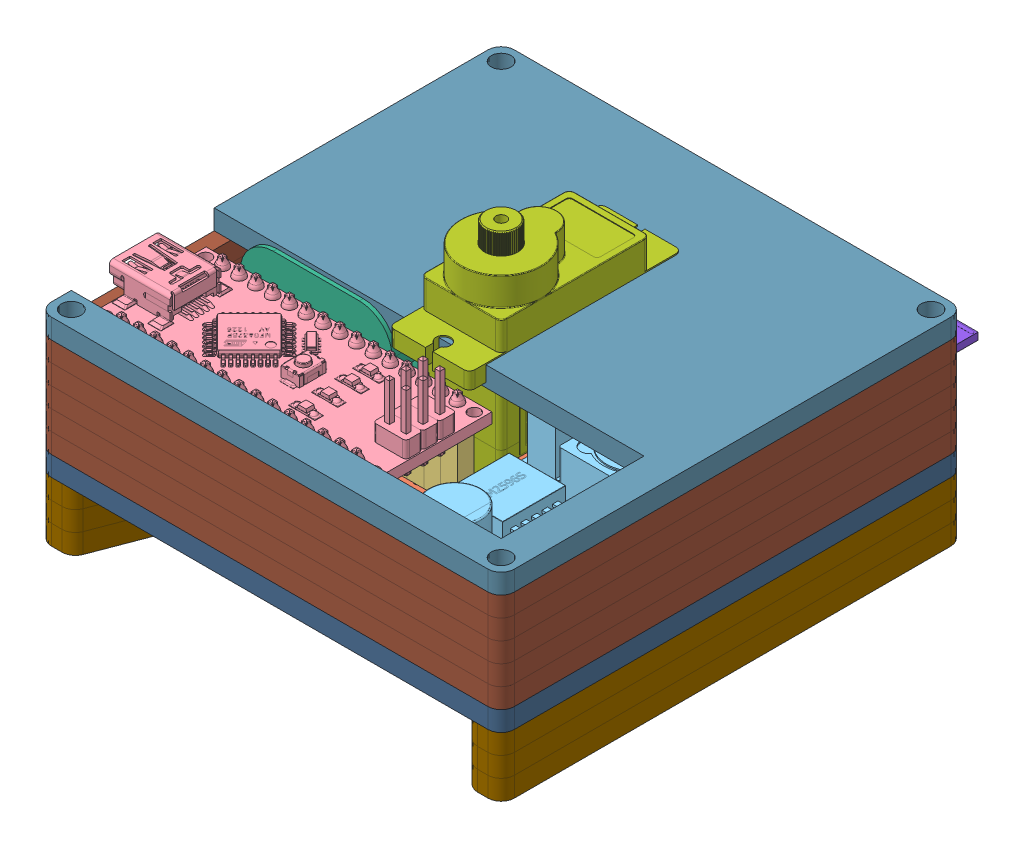
SolidWorks assembly base assembly, configuration Default. Lengths in mm.
Overall size (70 41.85 79.11).
27 component instances, 14 part files, 68 mates.
Components (placement in the parent):
- hex nut style 1_am-1: hex nut style 1_am [B18.2.4.1M - Hex nut, Style 1,  M3 x 0.5 --D-N] at (-15.0478 14.4 2.5048) x (1 0 0) z (0 1 0) size (5.5 6.35 2.4)
- hex nut style 1_am-2: hex nut style 1_am [B18.2.4.1M - Hex nut, Style 1,  M3 x 0.5 --D-N] at (-65.0478 12 2.5048) x (1 0 0) z (0 -1 0) size (5.5 6.35 2.4)
- hex nut style 1_am-3: hex nut style 1_am [B18.2.4.1M - Hex nut, Style 1,  M3 x 0.5 --D-N] at (-15.0478 14.4 52.5048) x (1 0 0) z (0 1 0) size (5.5 6.35 2.4)
- hex nut style 1_am-4: hex nut style 1_am [B18.2.4.1M - Hex nut, Style 1,  M3 x 0.5 --D-N] at (-65.0478 14.4 52.5048) x (1 0 0) z (0 1 0) size (5.5 6.35 2.4)
- pcb-2: pcb [Default] at (-72.9594 14.4 41.2771) x (0 0 1) z (-1 0 0) size (60 1 60)
- Arduino NanoV3 + Female Headers-1: Arduino NanoV3 + Female Headers [Default] at (-32.0594 27.95 40.8489) x (-1 0 0) z (0 0 1) size (38.1 11.45 17.78)
- arduino nano-1: arduino nano [Default] at (-36.1294 26.35 42.1189) x (-1 0 0) z (0 0 -1) size (45 18.6 18)
- LM2596 - small buck-1: LM2596 - small buck [Default] at (-14.6157 36.0469 15.8857) x (0 0 1) z (0 1 0) size (43.33 21.52 14.13)
- battery-1: battery [Default] at (-61.9173 22.4 17.6773) size (23 7 40)
- battery-2: battery [Default] at (-61.709 15.4 17.6773) size (23 7 40)
- SG90 - Micro Servo 9g - Tower Pro.1-1: SG90 - Micro Servo 9g - Tower Pro.1 [Peça] at (-42.9594 22.55 23.5273) x (0 0 -1) z (1 0 0) size (32.1 29.95 12.4)
- nRF24L01+_enhanced-1: nRF24L01+_enhanced [Default<As Machined>] at (-22.4594 18.449 -0.9285) x (0 0 -1) z (1 0 0) size (29 12.85 15)
- stage-1: stage [Default] at (-42.9594 0 28.6773) size (70 3 70)
- base1-1: base1 [Default] at (-42.9594 12 28.6773) x (-1 0 0) z (0 0 1) size (70 3 70)
- stage-2: stage [Default] at (-42.9594 3 28.6773) size (70 3 70)
- stage-3: stage [Default] at (-42.9594 6 28.6773) size (70 3 70)
- walls-1: walls [Default] at (-42.9594 12 28.6773) size (70 3 70)
- walls-2: walls [Default] at (-42.9594 15 28.6773) size (70 3 70)
- walls-3: walls [Default] at (-42.9594 18 28.6773) size (70 3 70)
- walls-4: walls [Default] at (-42.9594 21 28.6773) size (70 3 70)
- walls-5: walls [Default] at (-42.9594 24 28.6773) size (70 3 70)
- Header, Male, 2.54mm, 1x3-1: Header, Male, 2.54mm, 1x3 [Default] at (-33.4499 15.146 0.698) x (0 0 -1) z (1 0 0) size (7.62 11.54 2.54)
- Header, Male, 2.54mm, 1x3-2: Header, Male, 2.54mm, 1x3 [Default] at (-36.3022 15.146 0.7513) x (0 0 -1) z (1 0 0) size (7.62 11.54 2.54)
- Header, Male, 2.54mm, 1x2-1: Header, Male, 2.54mm, 1x2 [Default] at (-44.122 15.146 5.6481) size (5.08 11.54 2.54)
- Header, Male, 2.54mm, 1x2-2: Header, Male, 2.54mm, 1x2 [Default] at (-44.0543 15.146 2.787) size (5.08 11.54 2.54)
- Header, Male, 2.54mm, 1x2-3: Header, Male, 2.54mm, 1x2 [Default] at (-43.947 15.146 -0.0213) size (5.08 11.54 2.54)
- base1nano-1: base1nano [Default] at (-42.9594 27 28.6773) x (0 0 1) z (-1 0 0) size (70 3 70)
Mates (geometry in assembly coordinates):
- Coincident28: coincident anti-aligned: plane of stage-1 through (-41.8131 0 2.8151) normal (0 -1 0); plane of assembly through (0 0 0) normal (0 1 0)
- Coincident29: coincident anti-aligned: plane of stage-1 through (-41.8131 3 2.8151) normal (0 1 0); plane of stage-2 through (-41.8131 3 2.8151) normal (0 -1 0)
- Coincident30: coincident aligned: plane of stage-1 through (-77.9594 3 -6.3227) normal (-1 0 0); plane of stage-2 through (-77.9594 6 -6.3227) normal (-1 0 0)
- Concentric11: concentric aligned: cylinder of stage-1 through (-75.4594 0 61.1773) axis (0 1 0) radius 1.4881; cylinder of stage-2 through (-75.4594 3 61.1773) axis (0 1 0) radius 1.4881
- Coincident31: coincident anti-aligned: plane of stage-2 through (-41.8131 6 2.8151) normal (0 1 0); plane of stage-3 through (-41.8131 6 2.8151) normal (0 -1 0)
- Coincident32: coincident aligned: plane of stage-1 through (-77.9594 3 -6.3227) normal (-1 0 0); plane of stage-3 through (-77.9594 9 -6.3227) normal (-1 0 0)
- Concentric12: concentric aligned: cylinder of stage-1 through (-75.4594 0 61.1773) axis (0 1 0) radius 1.4881; cylinder of stage-3 through (-75.4594 6 61.1773) axis (0 1 0) radius 1.4881
- Coincident35: coincident anti-aligned: plane of base1-1 through (-42.9594 9 28.6773) normal (0 -1 0); plane of stage-3 through (-41.8131 9 2.8151) normal (0 1 0)
- Coincident36: coincident aligned: plane of base1-1 through (-77.9594 9 -6.3227) normal (-1 0 0); plane of stage-2 through (-77.9594 6 -6.3227) normal (-1 0 0)
- Concentric14: concentric aligned: cylinder of base1-1 through (-75.4594 9 61.1773) axis (0 1 0) radius 1.5; cylinder of stage-3 through (-75.4594 6 61.1773) axis (0 1 0) radius 1.4881
- Coincident37: coincident anti-aligned: plane of base1-1 through (-42.9594 12 28.6773) normal (0 1 0); plane of walls-1 through (-42.9594 12 28.6773) normal (0 -1 0)
- Coincident38: coincident aligned: plane of base1-1 through (-77.9594 9 -6.3227) normal (-1 0 0); plane of walls-1 through (-77.9594 15 -6.3227) normal (-1 0 0)
- Concentric15: concentric anti-aligned: cylinder of base1-1 through (-75.4594 9 61.1773) axis (0 1 0) radius 1.5; cylinder of walls-1 through (-75.4594 15 61.1773) axis (0 -1 0) radius 1.5
- Coincident39: coincident anti-aligned: plane of walls-1 through (-42.9594 15 28.6773) normal (0 1 0); plane of walls-2 through (-42.9594 15 28.6773) normal (0 -1 0)
- Coincident40: coincident aligned: plane of base1-1 through (-77.9594 9 -6.3227) normal (-1 0 0); plane of walls-2 through (-77.9594 18 -6.3227) normal (-1 0 0)
- Concentric16: concentric anti-aligned: cylinder of base1-1 through (-75.4594 9 61.1773) axis (0 1 0) radius 1.5; cylinder of walls-2 through (-75.4594 18 61.1773) axis (0 -1 0) radius 1.5
- Coincident41: coincident aligned: plane of base1-1 through (-77.9594 9 -6.3227) normal (-1 0 0); plane of walls-3 through (-77.9594 21 -6.3227) normal (-1 0 0)
- Concentric17: concentric anti-aligned: cylinder of base1-1 through (-75.4594 9 61.1773) axis (0 1 0) radius 1.5; cylinder of walls-3 through (-75.4594 21 61.1773) axis (0 -1 0) radius 1.5
- Coincident42: coincident anti-aligned: plane of walls-2 through (-42.9594 18 28.6773) normal (0 1 0); plane of walls-3 through (-42.9594 18 28.6773) normal (0 -1 0)
- Coincident43: coincident aligned: plane of base1-1 through (-77.9594 9 -6.3227) normal (-1 0 0); plane of walls-4 through (-77.9594 24 -6.3227) normal (-1 0 0)
- Concentric18: concentric anti-aligned: cylinder of base1-1 through (-75.4594 9 61.1773) axis (0 1 0) radius 1.5; cylinder of walls-4 through (-75.4594 24 61.1773) axis (0 -1 0) radius 1.5
- Coincident44: coincident anti-aligned: plane of walls-3 through (-42.9594 21 28.6773) normal (0 1 0); plane of walls-4 through (-42.9594 21 28.6773) normal (0 -1 0)
- Coincident45: coincident aligned: plane of base1-1 through (-77.9594 9 -6.3227) normal (-1 0 0); plane of walls-5 through (-77.9594 27 -6.3227) normal (-1 0 0)
- Concentric19: concentric anti-aligned: cylinder of base1-1 through (-75.4594 9 61.1773) axis (0 1 0) radius 1.5; cylinder of walls-5 through (-75.4594 27 61.1773) axis (0 -1 0) radius 1.5
- Coincident46: coincident anti-aligned: plane of walls-4 through (-42.9594 24 28.6773) normal (0 1 0); plane of walls-5 through (-42.9594 24 28.6773) normal (0 -1 0)
- Coincident49: coincident anti-aligned: plane of hex nut style 1_am-3 through (-20.5478 12 52.5048) normal (0 -1 0); plane of base1-1 through (-42.9594 12 28.6773) normal (0 1 0)
- Concentric21: concentric aligned: cylinder of hex nut style 1_am-3 through (-15.0478 12 52.5048) axis (0 1 0) radius 1.25; circle of assembly
- Coincident50: coincident anti-aligned: plane of hex nut style 1_am-1 through (-20.5478 12 2.5048) normal (0 -1 0); plane of base1-1 through (-42.9594 12 28.6773) normal (0 1 0)
- Concentric22: concentric aligned: cylinder of hex nut style 1_am-1 through (-15.0478 12 2.5048) axis (0 1 0) radius 1.25; circle of assembly
- Coincident51: coincident anti-aligned: plane of hex nut style 1_am-4 through (-70.5478 12 52.5048) normal (0 -1 0); plane of base1-1 through (-42.9594 12 28.6773) normal (0 1 0)
- Concentric23: concentric aligned: cylinder of hex nut style 1_am-4 through (-65.0478 12 52.5048) axis (0 1 0) radius 1.25; circle of assembly
- Coincident52: coincident anti-aligned: plane of hex nut style 1_am-2 through (-70.5478 12 2.5048) normal (0 -1 0); plane of base1-1 through (-42.9594 12 28.6773) normal (0 1 0)
- Concentric24: concentric anti-aligned: cylinder of hex nut style 1_am-2 through (-65.0478 14.4 2.5048) axis (0 -1 0) radius 1.25; circle of assembly
- Coincident53: coincident anti-aligned: plane of hex nut style 1_am-4 through (-70.5478 14.4 52.5048) normal (0 1 0); plane of pcb-2 through (-72.9594 14.4 41.2771) normal (0 -1 0)
- Concentric25: concentric anti-aligned: cylinder of SG90 - Micro Servo 9g - Tower Pro.1-1 through (-42.9594 38.75 28.6773) axis (0 -1 0) radius 6.1; circle of assembly
- Parallel8: parallel aligned: plane of SG90 - Micro Servo 9g - Tower Pro.1-1 through (-48.2094 12 12.2773) normal (0 0 -1); plane of walls-5 through (-77.9594 27 -6.3227) normal (0 0 -1)
- Coincident55: coincident anti-aligned: plane of SG90 - Micro Servo 9g - Tower Pro.1-1 through (-37.7094 12 33.9273) normal (0 -1 0); circle of assembly
- Parallel10: parallel: plane of SG90 - Micro Servo 9g - Tower Pro.1-1 through (-49.0594 30.2 38.7273) normal (-1 0 0); line of assembly
- Coincident58: coincident anti-aligned: plane of pcb-2 through (-49.0594 15.4 39.8789) normal (1 0 0); plane of SG90 - Micro Servo 9g - Tower Pro.1-1 through (-49.0594 30.2 38.7273) normal (-1 0 0)
- Lock2: lock: unknown of pcb-2; unknown of walls-5
- Coincident60: coincident anti-aligned: plane of pcb-2 through (-72.9594 15.4 41.2771) normal (0 1 0); plane of battery-2 through (-61.709 15.4 17.6773) normal (0 -1 0)
- Coincident64: coincident aligned: plane of battery-1 through (-73.4173 29.4 37.6773) normal (0 0 1); plane of battery-2 through (-73.209 22.4 37.6773) normal (0 0 1)
- Coincident65: coincident anti-aligned: plane of battery-1 through (-61.9173 22.4 17.6773) normal (0 -1 0); plane of battery-2 through (-61.709 22.4 17.6773) normal (0 1 0)
- Distance2: distance = 26 mm aligned: plane of battery-2 through (-73.209 22.4 37.6773) normal (0 0 1); plane of walls-4 through (-77.9594 24 63.6773) normal (0 0 1)
- Coincident67: coincident anti-aligned: plane of pcb-2 through (-72.9594 15.4 41.2771) normal (0 1 0); plane of LM2596 - small buck-1 through (-23.7804 15.4 36.9128) normal (0 -1 0)
- Coincident68: coincident: line of pcb-2 through (-72.9594 15.4 58.6289) axis (1 0 0); plane of LM2596 - small buck-1 through (-16.909 16.9539 58.6289) normal (0 0 1)
- Coincident69: coincident anti-aligned: plane of pcb-2 through (-72.9594 15.4 41.2771) normal (0 1 0); plane of nRF24L01+_enhanced-1 through (-19.0894 15.4 10.8015) normal (0 -1 0)
- Distance3: distance = 2 mm: plane of nRF24L01+_enhanced-1 through (-14.9594 18.949 13.5715) normal (1 0 0); line of pcb-2 through (-12.9594 15.4 58.6289) axis (0 0 -1)
- Coincident72: coincident anti-aligned: plane of pcb-2 through (-72.9594 15.4 41.2771) normal (0 1 0); plane of Arduino NanoV3 + Female Headers-1 through (-58.9894 15.4 42.1189) normal (0 -1 0)
- Coincident73: coincident: line of pcb-2 through (-72.9594 15.4 58.6289) axis (1 0 0); plane of Arduino NanoV3 + Female Headers-1 through (-39.9394 15.4 58.6289) normal (0 0 1)
- Coincident74: coincident: line of pcb-2 through (-72.9594 15.4 -1.3711) axis (0 0 1); plane of Arduino NanoV3 + Female Headers-1 through (-72.9594 15.4 56.0889) normal (-1 0 0)
- Coincident75: coincident anti-aligned: plane of Arduino NanoV3 + Female Headers-1 through (-53.9094 23.85 57.3589) normal (0 1 0); plane of arduino nano-1 through (-36.8994 23.85 56.5889) normal (0 -1 0)
- Coincident76: coincident aligned: plane of Arduino NanoV3 + Female Headers-1 through (-50.0994 15.4 58.6289) normal (0 0 1); plane of arduino nano-1 through (-47.0594 23.85 58.6289) normal (0 0 1)
- Coincident77: coincident aligned: plane of Arduino NanoV3 + Female Headers-1 through (-34.8594 15.4 58.6289) normal (1 0 0); plane of arduino nano-1 through (-34.8594 23.85 58.1289) normal (1 0 0)
- Lock3: lock: unknown of base1-1
- Coincident79: coincident anti-aligned: plane of pcb-2 through (-72.9594 15.4 41.2771) normal (0 1 0); plane of Header, Male, 2.54mm, 1x3-1 through (-33.4499 15.4 5.778) normal (0 -1 0)
- Parallel13: parallel: line of pcb-2 through (-12.9594 15.4 58.6289) axis (0 0 -1); plane of Header, Male, 2.54mm, 1x3-1 through (-34.7199 17.686 4.508) normal (-1 0 0)
- Coincident81: coincident anti-aligned: plane of pcb-2 through (-72.9594 15.4 41.2771) normal (0 1 0); plane of Header, Male, 2.54mm, 1x3-2 through (-36.3022 15.4 5.8313) normal (0 -1 0)
- Parallel14: parallel: line of pcb-2 through (-12.9594 15.4 58.6289) axis (0 0 -1); plane of Header, Male, 2.54mm, 1x3-2 through (-37.5722 17.686 4.5613) normal (-1 0 0)
- Parallel16: parallel aligned: plane of walls-2 through (-77.9594 18 -6.3227) normal (0 0 -1); plane of Header, Male, 2.54mm, 1x2-1 through (-45.392 17.686 4.3781) normal (0 0 -1)
- Coincident86: coincident anti-aligned: plane of pcb-2 through (-72.9594 15.4 41.2771) normal (0 1 0); plane of Header, Male, 2.54mm, 1x2-1 through (-46.662 15.4 5.6481) normal (0 -1 0)
- Parallel18: parallel aligned: plane of walls-2 through (-77.9594 18 -6.3227) normal (0 0 -1); plane of Header, Male, 2.54mm, 1x2-2 through (-45.3243 17.686 1.517) normal (0 0 -1)
- Coincident87: coincident anti-aligned: plane of pcb-2 through (-72.9594 15.4 41.2771) normal (0 1 0); plane of Header, Male, 2.54mm, 1x2-2 through (-46.5943 15.4 2.787) normal (0 -1 0)
- Parallel19: parallel aligned: plane of walls-2 through (-77.9594 18 -6.3227) normal (0 0 -1); plane of Header, Male, 2.54mm, 1x2-3 through (-45.217 17.686 -1.2913) normal (0 0 -1)
- Coincident88: coincident anti-aligned: plane of pcb-2 through (-72.9594 15.4 41.2771) normal (0 1 0); plane of Header, Male, 2.54mm, 1x2-3 through (-46.487 15.4 -0.0213) normal (0 -1 0)
- Concentric26: concentric: cylinder of walls-5 through (-10.4594 27 -3.8227) axis (0 -1 0) radius 1.5; cylinder of base1nano-1 through (-10.4594 30 -3.8227) axis (0 -1 0) radius 1.5
- Coincident90: coincident: plane of walls-5 through (-42.9594 27 28.6773) normal (0 1 0); plane of base1nano-1 through (-42.9594 27 28.6773) normal (0 -1 0)
- Coincident91: coincident aligned: plane of walls-4 through (-77.9594 24 -6.3227) normal (0 0 -1); plane of base1nano-1 through (-7.9594 30 -6.3227) normal (0 0 -1)
